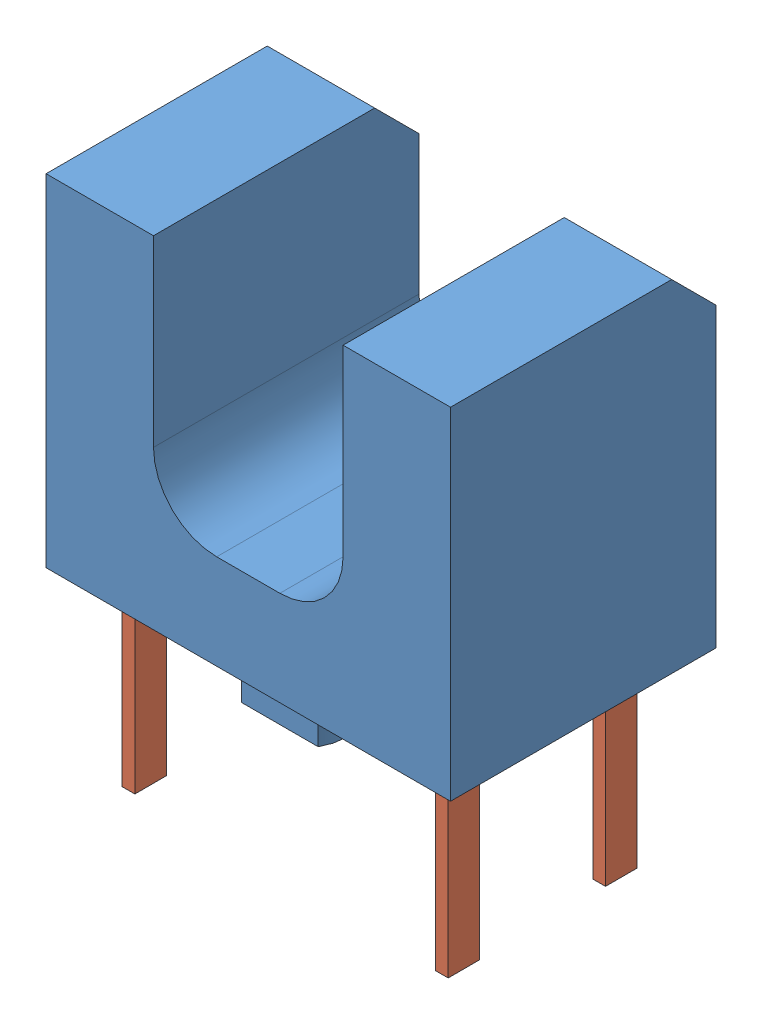
SolidWorks assembly rpi-352, configuration По умолчанию. Lengths in mm.
Overall size (6.41 8.4 4.21).
2 component instances, 2 part files, 0 mates.
Components (placement in the parent):
- rpi-352_body-1: rpi-352_body [По умолчанию] at (-3.1225 -2.6643 6.4) size (6.4 6.2 4.2)
- rpi-352_legs-1: rpi-352_legs [По умолчанию] at (-3.1225 -2.6643 10.6) x (0.999998 0 -0.002187) z (-0.002187 0 -0.999998) size (6.4 3 4.2)
